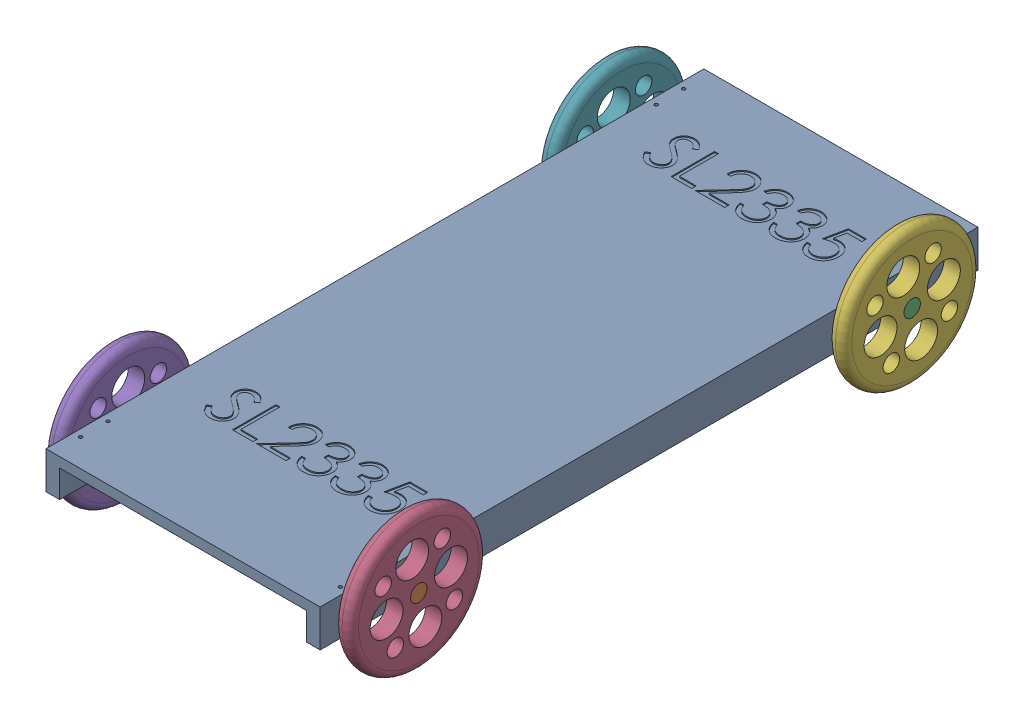
SolidWorks assembly rolling_chassis, configuration Default. Lengths in mm.
Overall size (560 308.26 1204.13).
7 component instances, 3 part files, 14 mates.
Components (placement in the parent):
- chassis_sl2335-1: chassis_sl2335 [Default] at origin size (500 68 1200)
- axle_sl2335-1: axle_sl2335 [Default] at (-30 30 1050) size (560 30 30)
- axle_sl2335-3: axle_sl2335 [Default] at (-30 30 150) size (560 30 30)
- wheel_sl2335-2: wheel_sl2335 [Default] at (530 30 1050) x (0 0.20057 -0.979679) z (-1 0 0) size (250 250 30)
- wheel_sl2335-3: wheel_sl2335 [Default] at (-30 30 1050) x (0 0 -1) z (1 0 0) size (250 250 30)
- wheel_sl2335-4: wheel_sl2335 [Default] at (500 30 150) x (0 0.270269 -0.962785) z (1 0 0) size (250 250 30)
- wheel_sl2335-5: wheel_sl2335 [Default] at (-30 30 150) x (0 -0.970297 -0.241915) z (1 0 0) size (250 250 30)
Mates (geometry in assembly coordinates):
- Concentric1: concentric anti-aligned: cylinder of chassis_sl2335-1 through (-700 30 1050) axis (1 0 0) radius 15; cylinder of axle_sl2335-1 through (530 30 1050) axis (-1 0 0) radius 15
- Concentric2: concentric anti-aligned: circle of chassis_sl2335-1; cylinder of axle_sl2335-1 through (530 30 1050) axis (-1 0 0) radius 15
- Concentric7: concentric anti-aligned: cylinder of chassis_sl2335-1 through (-700 30 150) axis (1 0 0) radius 15; cylinder of axle_sl2335-3 through (530 30 150) axis (-1 0 0) radius 15
- Concentric8: concentric anti-aligned: cylinder of chassis_sl2335-1 through (-700 30 150) axis (1 0 0) radius 15; cylinder of axle_sl2335-3 through (530 30 150) axis (-1 0 0) radius 15
- Concentric10: concentric aligned: cylinder of axle_sl2335-1 through (530 30 1050) axis (-1 0 0) radius 15; cylinder of wheel_sl2335-2 through (530 30 1050) axis (-1 0 0) radius 15
- Coincident2: coincident anti-aligned: plane of chassis_sl2335-1 through (500 68 1200) normal (1 0 0); plane of wheel_sl2335-2 through (500 30 1050) normal (-1 0 0)
- Concentric11: concentric anti-aligned: cylinder of axle_sl2335-1 through (530 30 1050) axis (-1 0 0) radius 15; cylinder of wheel_sl2335-3 through (-30 30 1050) axis (1 0 0) radius 15
- Coincident3: coincident anti-aligned: plane of chassis_sl2335-1 through (0 0 1200) normal (-1 0 0); plane of wheel_sl2335-3 through (0 30 1050) normal (1 0 0)
- Concentric12: concentric anti-aligned: cylinder of axle_sl2335-3 through (530 30 150) axis (-1 0 0) radius 15; cylinder of wheel_sl2335-4 through (500 30 150) axis (1 0 0) radius 15
- Coincident4: coincident anti-aligned: plane of chassis_sl2335-1 through (500 68 1200) normal (1 0 0); plane of wheel_sl2335-4 through (500 30 150) normal (-1 0 0)
- Concentric13: concentric anti-aligned: cylinder of axle_sl2335-3 through (530 30 150) axis (-1 0 0) radius 15; cylinder of wheel_sl2335-5 through (-30 30 150) axis (1 0 0) radius 15
- Coincident5: coincident anti-aligned: plane of chassis_sl2335-1 through (0 0 1200) normal (-1 0 0); plane of wheel_sl2335-5 through (0 30 150) normal (1 0 0)
- Coincident6: coincident aligned: plane of axle_sl2335-3 through (530 30 150) normal (1 0 0); plane of wheel_sl2335-4 through (530 30 150) normal (1 0 0)
- Coincident8: coincident aligned: circle of axle_sl2335-1; circle of wheel_sl2335-3
